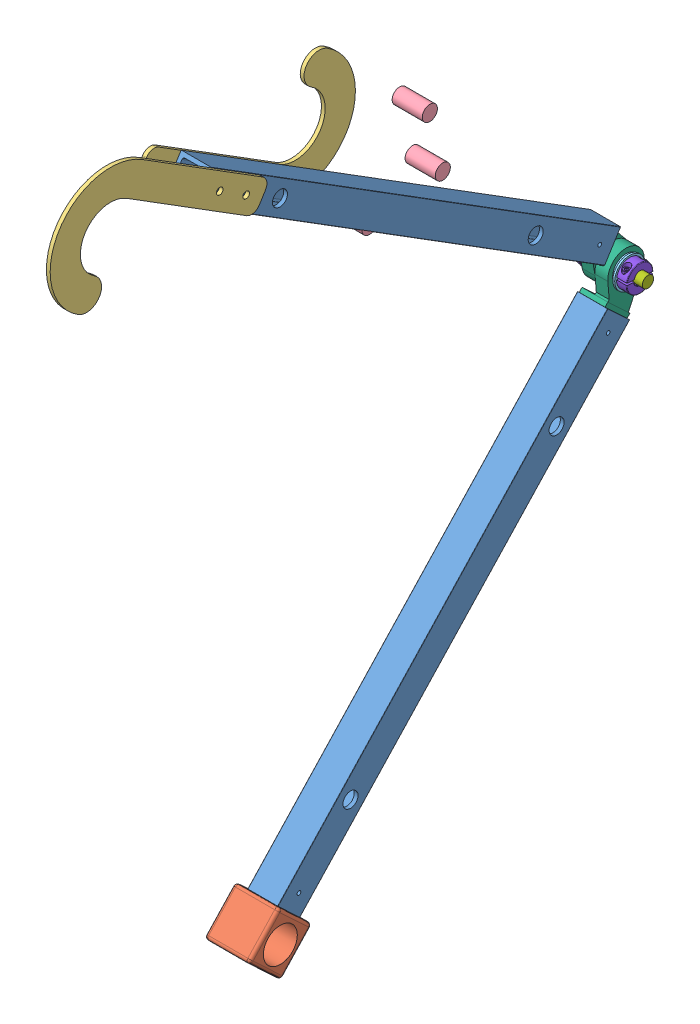
SolidWorks assembly new endcaps climber, configuration Default. Lengths in mm.
Overall size (59.8 696.85 544.81).
19 component instances, 9 part files, 57 mates.
Components (placement in the parent):
- chasis box for climber prototype-1: chasis box for climber prototype [Default] at (1583.147 1030.9002 1775.5006) size (711.2 101.6 711.2) (hidden)
- 1x1x20 box extrusion for climber-1: 1x1x20 box extrusion for climber [Default] at (1887.947 1429.2862 1701.0696) x (1 0 0) z (0 -0.730281 0.683147) size (25.4 25.4 406.4)
- 1x1x20 box extrusion for climber-2: 1x1x20 box extrusion for climber [Default] at (1887.947 1716.5835 2053.2453) x (1 0 0) z (0 -0.530403 -0.847746) size (25.4 25.4 406.4)
- End Bearing Holder-2: End Bearing Holder [Default] at (1900.012 1150.0169 1978.8355) x (0 -0.683147 -0.730281) z (-1 0 0) size (38.1 50.8 38.1)
- Candy cane claw-3: Candy cane claw [Default] at (1884.772 1725.4156 2082.7296) x (0 -0.847746 0.530403) z (1 0 0) size (101.6 177.8 3.17)
- Candy cane claw-4: Candy cane claw [Default] at (1913.347 1672.3184 2015.9742) x (0 0.847746 -0.530403) z (1 0 0) size (101.6 177.8 3.17)
- 1in Spacers-1: 1in Spacers [Default] at (1887.947 1596.2084 1885.4367) size (25.4 12.7 12.7)
- 1in Spacers-2: 1in Spacers [Default] at (1887.947 1607.3675 1920.0929) x (1 0 0) z (0 -0.04871 -0.998813) size (25.4 12.7 12.7)
- 1in Spacers-3: 1in Spacers [Default] at (1887.947 1600.1448 1880.8132) x (1 0 0) z (0 -0.102933 -0.994688) size (25.4 12.7 12.7)
- 1in Spacers-4: 1in Spacers [Default] at (1887.947 1664.3228 1869.2984) x (1 0 0) z (0 -0.102933 -0.994688) size (25.4 12.7 12.7)
- 1in Spacers-5: 1in Spacers [Default] at (1913.347 1616.1159 1858.3947) x (-1 0 0) z (0 0.95862 0.284688) size (25.4 12.7 12.7)
- AA Climb Insert v2-1: AA Climb Insert v2 [Default] at (1893.6743 1450.8733 1620.9039) x (0 -0.100273 -0.99496) z (0 -0.99496 0.100273) size (92.26 59.8 115.41)
  - Ball Bearing-1: Ball Bearing [Default] at (-81.0287 -2.4491 -5.6602) x (1 0 0) z (0 1 0) size (25.4 25.4 10.32)
  - Climber Insert 1-1: Climber Insert 1 [Default] at (-136.2666 -5.4773 -34.7042) x (0.442723 0 -0.896658) z (0.896658 0 0.442723) size (40.77 21.73 77.76)
  - Ball Bearing-2: Ball Bearing [Default] at (-81.0287 15.3865 -4.7702) x (1 0 0) z (0 -1 0) size (25.4 25.4 10.32)
  - Climber Insert 1-2: Climber Insert 1 [Default] at (-117.6033 16.7477 44.9074) x (0.795102 0 0.606476) z (0.606476 0 -0.795102) size (40.77 21.73 77.76)
  - Rotary Shaft-1: Rotary Shaft [Default] at (-81.0287 -2.4491 -5.6602) x (1 0 0) z (0 -1 0) size (9.53 9.53 59.8)
  - Clamping Two-Piece Shaft Collar-1: Clamping Two-Piece Shaft Collar [Default] at (-81.0287 -10.5629 -5.6602) x (1 0 0) z (0 -1 0) size (22.18 22.23 9.54)
  - Clamping Two-Piece Shaft Collar-2: Clamping Two-Piece Shaft Collar [Default] at (-81.0287 23.5002 -4.7702) x (1 0 0) z (0 1 0) size (22.18 22.23 9.54)
Mates (geometry in assembly coordinates):
- Concentric12: concentric anti-aligned: cylinder of Bracket for climber prototype-5 through (1884.6185 1590.052 2083.5041) axis (0.99927 0.016824 0.034303) radius 2.667; cylinder of Candy cane claw-1 through (1912.1504 1590.0497 2083.9107) axis (-0.999875 -0.006957 -0.014212) radius 2.794
- Parallel10: parallel anti-aligned: cylinder of Bracket for climber prototype-3 through (1883.6189 1601.5639 2106.9759) axis (0.99927 0.016824 0.034303) radius 2.667; cylinder of Candy cane claw-1 through (1911.7364 1601.5502 2107.4057) axis (-0.999875 -0.006957 -0.014212) radius 2.794
- Coincident15: coincident anti-aligned: plane of Bracket for climber prototype-3 through (1911.8046 1608.5657 2093.2762) normal (-0.99927 -0.016824 -0.034303); plane of Candy cane claw-1 through (1910.3974 1604.4765 2200.1781) normal (0.999875 0.006957 0.014212)
- Concentric14: concentric anti-aligned: cylinder of Bracket for climber prototype-3 through (1883.6189 1601.5639 2106.9759) axis (0.99927 0.016824 0.034303) radius 2.667; cylinder of Candy cane claw-1 through (1911.7364 1601.5502 2107.4057) axis (-0.999875 -0.006957 -0.014212) radius 2.794
- Concentric15: concentric aligned: cylinder of Bracket for climber prototype-6 through (1833.3636 1600.7178 2105.2508) axis (-0.99927 -0.016824 -0.034303) radius 2.667; cylinder of Candy cane claw-2 through (1808.7436 1600.3033 2104.4056) axis (-0.99927 -0.016824 -0.034303) radius 2.794
- Concentric16: concentric aligned: cylinder of Bracket for climber prototype-4 through (1834.3632 1589.2059 2081.7789) axis (-0.99927 -0.016824 -0.034303) radius 2.667; cylinder of Candy cane claw-2 through (1809.7432 1588.7914 2080.9338) axis (-0.99927 -0.016824 -0.034303) radius 2.794
- Coincident16: coincident anti-aligned: plane of Bracket for climber prototype-6 through (1805.1779 1615.8368 2108.1013) normal (0.99927 0.016824 0.034303); plane of Candy cane claw-2 through (1802.3378 1603.2262 2197.0208) normal (-0.99927 -0.016824 -0.034303)
- Concentric18: concentric aligned: circle of Hex shaft for climber-1; circle of wood piece for pivot in climber-1
- Coincident23: coincident aligned: plane of shortHex shaft for climber-1 through (1858.991 1609.2959 2087.5547) normal (0 -0.897828 0.440346); plane of wood piece for pivot in climber-1 through (1858.991 1609.2959 2087.5547) normal (0 -0.897828 0.440346)
- Concentric21: concentric aligned: circle of half in hex bearing for clibmer-1; circle of Hex shaft for climber-1
- Coincident32: coincident aligned: plane of half in hex bearing for clibmer-1 through (1858.991 1609.2959 2087.5547) normal (0 -0.897828 0.440346); plane of wood piece for pivot in climber-1 through (1858.991 1609.2959 2087.5547) normal (0 -0.897828 0.440346)
- Parallel15: parallel anti-aligned: line of Bracket for climber prototype-3 through (1884.0119 1610.9483 2090.924) axis (0.99927 0.016824 0.034303); line of Bracket for climber prototype-6 through (1833.7566 1610.1022 2089.1988) axis (-0.99927 -0.016824 -0.034303)
- Parallel16: parallel anti-aligned: line of Bracket for climber prototype-4 through (1833.9701 1607.6434 2084.1854) axis (-0.99927 -0.016824 -0.034303); line of Bracket for climber prototype-5 through (1884.2254 1608.4895 2085.9106) axis (0.99927 0.016824 0.034303)
- Coincident38: coincident anti-aligned: plane of Bracket for climber prototype-5 through (1912.8042 1597.0537 2069.8043) normal (-0.99927 -0.016824 -0.034303); plane of Candy cane claw-1 through (1910.3974 1604.4765 2200.1781) normal (0.999875 0.006957 0.014212)
- Concentric23: concentric aligned: cylinder of Bracket for climber prototype-3 through (1899.1016 1587.9136 2114.3301) axis (0 0.897828 -0.440346) radius 2.794; cylinder of wood piece for pivot in climber-1 through (1899.1016 1615.7355 2100.6847) axis (0 0.897828 -0.440346) radius 3.175
- Concentric24: concentric aligned: cylinder of Bracket for climber prototype-5 through (1900.1011 1576.4017 2090.8583) axis (0 0.897828 -0.440346) radius 2.794; cylinder of wood piece for pivot in climber-1 through (1900.1011 1604.2236 2077.2129) axis (0 0.897828 -0.440346) radius 3.175
- Concentric25: concentric aligned: cylinder of Bracket for climber prototype-6 through (1817.8809 1586.5462 2111.542) axis (0 0.897828 -0.440346) radius 2.794; cylinder of wood piece for pivot in climber-1 through (1817.8809 1614.3681 2097.8966) axis (0 0.897828 -0.440346) radius 3.175
- Concentric26: concentric aligned: cylinder of Bracket for climber prototype-4 through (1818.8805 1575.0343 2088.0702) axis (0 0.897828 -0.440346) radius 2.794; cylinder of wood piece for pivot in climber-1 through (1818.8805 1602.8562 2074.4247) axis (0 0.897828 -0.440346) radius 3.175
- Coincident40: coincident anti-aligned: plane of Bracket for climber prototype-6 through (1802.0052 1618.6339 2106.5943) normal (0 0.897828 -0.440346); plane of wood piece for pivot in climber-1 through (1858.991 1609.2959 2087.5547) normal (0 -0.897828 0.440346)
- Coincident41: coincident anti-aligned: plane of Bracket for climber prototype-3 through (1914.9773 1611.4697 2091.987) normal (0 0.897828 -0.440346); plane of wood piece for pivot in climber-1 through (1858.991 1609.2959 2087.5547) normal (0 -0.897828 0.440346)
- Parallel18: parallel anti-aligned: plane of half in hex bearing for clibmer-1 through (1866.3234 1616.4132 2084.0639) normal (-0.866025 -0.220173 -0.448914); plane of shortHex shaft for climber-1 through (1866.3234 1609.2959 2087.5547) normal (0.866025 0.220173 0.448914)
- Coincident42: coincident aligned: line of chasis box for climber prototype-1 through (1913.347 1132.5002 1978.7006) axis (-1 0 0); line of 1x1x20 box extrusion for climber-1 through (1913.093 1132.5002 1978.7006) axis (-1 0 0)
- Coincident43: coincident aligned: plane of chasis box for climber prototype-1 through (1913.347 1132.5002 1978.7006) normal (1 0 0); plane of 1x1x20 box extrusion for climber-1 through (1913.347 1149.6786 1997.0643) normal (1 0 0)
- Concentric27: concentric anti-aligned: circle of Hex shaft for climber-1; circle of half in hex bearing for clibmer-2
- Coincident49: coincident aligned: plane of shortHex shaft for climber-1 through (1858.991 1652.0549 2066.5832) normal (0 0.897828 -0.440346); plane of 1x1x20 box extrusion for climber-2 through (1913.093 1501.0277 1708.7215) normal (0 0.847746 -0.530403)
- Distance1: distance = 12.7 mm aligned: plane of shortHex shaft for climber-1 through (1862.6572 1612.0921 2093.2559) normal (0 0.440346 0.897828); plane of 1x1x20 box extrusion for climber-2 through (1888.201 1716.3681 2053.38) normal (0 0.530403 0.847746)
- Distance2: distance = 12.7 mm: point of shortHex shaft for climber-1; line of 1x1x20 box extrusion for climber-2 through (1888.201 1501.0277 1708.7215) axis (0 0.530403 0.847746)
- Coincident52: coincident anti-aligned: plane of half in hex bearing for clibmer-2 through (1866.8167 1624.1542 2067.378) normal (0 0.897828 -0.440346); plane of 1x1x20 box extrusion for climber-2 through (1888.201 1479.495 1722.1937) normal (0 -0.847746 0.530403)
- Tangent7: tangent anti-aligned: plane of 1x1x20 box extrusion for climber-1 through (1888.201 1149.8521 1997.2498) normal (0 0.683147 0.730281); cylinder of left Torsion Spring-1 through (1906.997 1481.4751 1709.0743) axis (0 -0.752236 0.658893) radius 1.7145
- Distance9: distance = 6.35 mm: plane of 1x1x20 box extrusion for climber-1 through (1913.347 1149.6786 1997.0643) normal (1 0 0); cylinder of left Torsion Spring-1 through (1906.997 1481.4751 1709.0743) axis (0 -0.752236 0.658893) radius 1.7145
- Tangent12: tangent anti-aligned: plane of 1x1x20 box extrusion for climber-1 through (1888.201 1149.8521 1997.2498) normal (0 0.683147 0.730281); face of ?
- Coincident81: coincident anti-aligned: plane of 1x1x20 box extrusion for climber-1 through (1891.122 1146.5986 1993.7718) normal (1 0 0); plane of End Bearing Holder-2 through (1891.122 1146.8155 1994.0037) normal (-1 0 0)
- Coincident82: coincident anti-aligned: plane of 1x1x20 box extrusion for climber-1 through (1892.7095 1134.6692 1981.0193) normal (0 0.683147 0.730281); plane of End Bearing Holder-2 through (1891.122 1134.6692 1981.0193) normal (0 -0.683147 -0.730281)
- Coincident83: coincident anti-aligned: plane of 1x1x20 box extrusion for climber-1 through (1888.201 1132.6737 1978.8861) normal (0 -0.730281 0.683147); plane of End Bearing Holder-2 through (1900.012 1140.7424 1987.5115) normal (0 0.730281 -0.683147)
- Coincident90: coincident anti-aligned: plane of 1x1x20 box extrusion for climber-2 through (1887.947 1500.8124 1708.8562) normal (-1 0 0); plane of Candy cane claw-3 through (1887.947 1686.3315 1957.374) normal (1 0 0)
- Concentric38: concentric anti-aligned: circle of 1x1x20 box extrusion for climber-2; circle of Candy cane claw-3
- Parallel19: parallel: plane of 1x1x20 box extrusion for climber-2 through (1888.201 1479.495 1722.1937) normal (0 -0.847746 0.530403); line of Candy cane claw-3 through (1887.947 1664.7988 1970.8463) axis (0 0.530403 0.847746)
- Coincident92: coincident anti-aligned: plane of 1x1x20 box extrusion for climber-2 through (1913.347 1479.7103 1722.059) normal (1 0 0); plane of Candy cane claw-4 through (1913.347 1711.4025 2141.3298) normal (-1 0 0)
- Concentric39: concentric anti-aligned: circle of 1x1x20 box extrusion for climber-2; circle of Candy cane claw-4
- Parallel20: parallel aligned: plane of 1x1x20 box extrusion for climber-2 through (1913.093 1501.0277 1708.7215) normal (0 0.847746 -0.530403); plane of Candy cane claw-4 through (1916.522 1691.1484 2013.1815) normal (0 0.847746 -0.530403)
- Coincident95: coincident anti-aligned: plane of Candy cane claw-4 through (1913.347 1711.4025 2141.3298) normal (-1 0 0); plane of 1in Spacers-1 through (1913.347 1596.2084 1885.4367) normal (1 0 0)
- Distance10: distance = 13.0413 mm: cylinder of 1in Spacers-1 through (1913.347 1596.2084 1885.4367) axis (-1 0 0) radius 6.35; plane of 1x1x20 box extrusion for climber-2 through (1913.093 1501.0277 1708.7215) normal (0 0.847746 -0.530403)
- Coincident96: coincident anti-aligned: plane of Candy cane claw-3 through (1887.947 1686.3315 1957.374) normal (1 0 0); plane of 1in Spacers-2 through (1887.947 1607.3675 1920.0929) normal (-1 0 0)
- Distance11: distance = 36.4085 mm: cylinder of 1in Spacers-2 through (1913.347 1607.3675 1920.0929) axis (-1 0 0) radius 6.35; cylinder of 1in Spacers-1 through (1913.347 1596.2084 1885.4367) axis (-1 0 0) radius 6.35
- Coincident98: coincident anti-aligned: plane of Candy cane claw-3 through (1887.947 1686.3315 1957.374) normal (1 0 0); plane of 1in Spacers-3 through (1887.947 1600.1448 1880.8132) normal (-1 0 0)
- Coincident99: coincident anti-aligned: plane of Candy cane claw-4 through (1913.347 1711.4025 2141.3298) normal (-1 0 0); plane of 1in Spacers-4 through (1913.347 1664.3228 1869.2984) normal (1 0 0)
- Coincident100: coincident anti-aligned: plane of Candy cane claw-3 through (1887.947 1686.3315 1957.374) normal (1 0 0); plane of 1in Spacers-5 through (1887.947 1616.1159 1858.3947) normal (-1 0 0)
- Lock2: lock: unknown of Candy cane claw-4; unknown of 1in Spacers-2
- Lock3: lock: unknown of Candy cane claw-4; unknown of 1in Spacers-3
- Lock4: lock: unknown of Candy cane claw-4; unknown of 1in Spacers-5
- Lock5: lock: unknown of Candy cane claw-4; unknown of 1in Spacers-4
- Coincident104: coincident anti-aligned: plane of 1x1x20 box extrusion for climber-1 through (1908.5845 1147.6831 1994.9311) normal (0 -0.683147 -0.730281); plane of AA Climb Insert v2-1/Climber Insert 1-2 through (1888.447 1417.814 1742.235) normal (0 0.683147 0.730281)
- Coincident105: coincident anti-aligned: plane of 1x1x20 box extrusion for climber-1 through (1910.172 1135.7537 1982.1786) normal (-1 0 0); plane of AA Climb Insert v2-1/Climber Insert 1-2 through (1910.172 1417.814 1742.235) normal (1 0 0)
- Coincident106: coincident anti-aligned: plane of 1x1x20 box extrusion for climber-1 through (1888.201 1429.4598 1701.2551) normal (0 0.730281 -0.683147); plane of AA Climb Insert v2-1/Climber Insert 1-2 through (1910.172 1428.3725 1700.0928) normal (0 -0.730281 0.683147)
- Coincident107: coincident anti-aligned: plane of 1x1x20 box extrusion for climber-2 through (1892.7095 1498.3361 1710.4055) normal (0 -0.847746 0.530403); plane of AA Climb Insert v2-1/Climber Insert 1-1 through (1888.447 1517.6958 1741.3482) normal (0 0.847746 -0.530403)
- Coincident110: coincident anti-aligned: plane of 1x1x20 box extrusion for climber-2 through (1910.172 1496.9903 1711.2475) normal (-1 0 0); plane of AA Climb Insert v2-1/Climber Insert 1-1 through (1910.172 1517.6958 1741.3482) normal (1 0 0)
- Coincident111: coincident anti-aligned: plane of 1x1x20 box extrusion for climber-2 through (1888.201 1500.8124 1708.8562) normal (0 -0.530403 -0.847746); plane of AA Climb Insert v2-1/Climber Insert 1-1 through (1888.447 1499.8938 1709.4309) normal (0 0.530403 0.847746)
